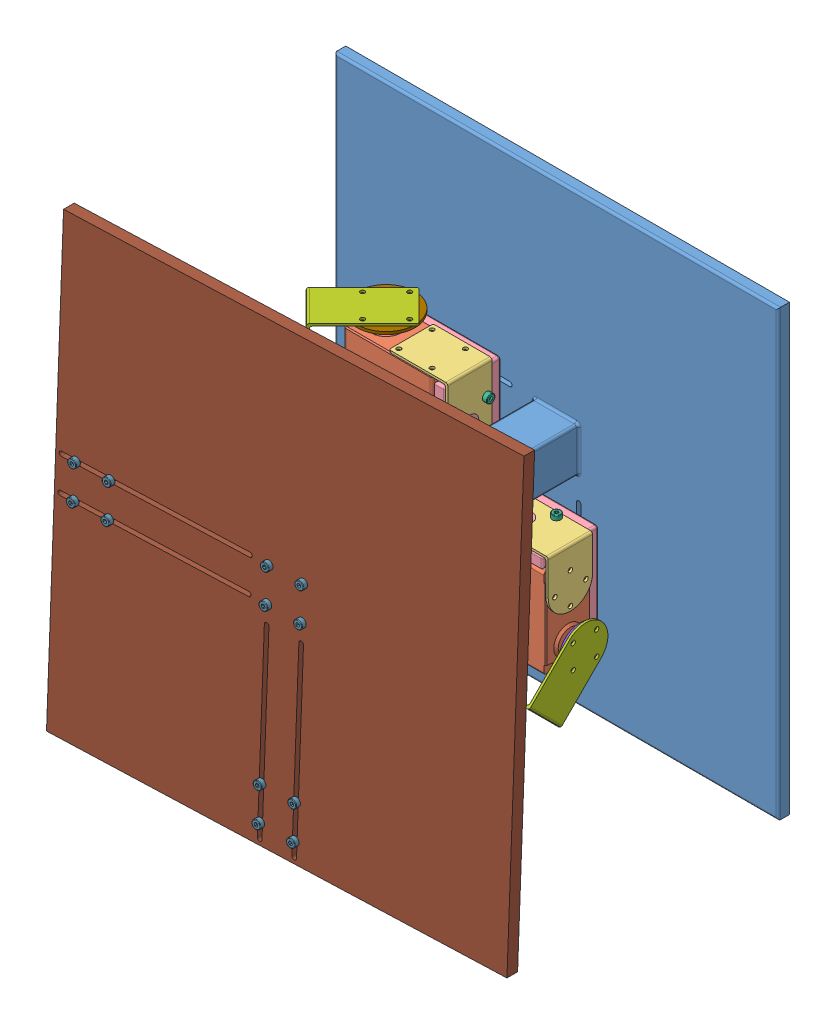
SolidWorks assembly systeme, configuration Défaut. Lengths in mm.
Overall size (200.85 201.15 137.65).
92 component instances, 17 part files, 49 mates.
Components (placement in the parent):
- socle-1: socle [Défaut] at (-2.0735 3.594 197.5) size (200 200 95)
- moteur-complet-1: moteur-complet [Défaut] at (-58.3742 32.144 216.6116) x (-1 0 0) z (0 -1 0) size (49 25.5 42.5)
  - moteur-1: moteur [Défaut] at (-9.5825 -1.0731 48.8) size (45.5 20 48.8)
  - moteur-support-fixe-1: moteur-support-fixe [Défaut] at (-5.7196 9.1116 16.94) x (1 0 0) z (0 -1 0) size (26.58 42.5 20)
  - moteur_semelle-1: moteur_semelle [Défaut] at (-31.3007 -10.8884 28.55) x (-1 0 0) z (0 0 1) size (47 25 38)
  - ecrou-h-m2-1: ecrou-h-m2 [6007 HU M2] at (-27.7007 -8.3884 21.05) x (0 0.5 -0.866025) z (0 -0.866025 -0.5) size (4 1.6 4.62)
  - ecrou-h-m2-2: ecrou-h-m2 [6007 HU M2] at (-27.7007 -8.3884 36.05) x (0 -0.5 -0.866025) z (0 -0.866025 0.5) size (4 1.6 4.62)
  - ecrou-h-m2-3: ecrou-h-m2 [6007 HU M2] at (-27.7007 6.6116 36.05) x (0 -0.5 -0.866025) z (0 -0.866025 0.5) size (4 1.6 4.62)
  - ecrou-h-m2-4: ecrou-h-m2 [6007 HU M2] at (-27.7007 6.6116 21.05) x (0 -1 0) z (0 0 1) size (4 1.6 4.62)
  - vis-chc-m2x5-1: vis-chc-m2x5 [Vis CHC M2x5] at (-32.3007 -8.3884 36.05) x (0 -0.454411 0.890792) z (0 -0.890792 -0.454411) size (3.8 7 3.8)
  - vis-chc-m2x5-2: vis-chc-m2x5 [Vis CHC M2x5] at (-32.3007 6.6116 36.05) x (0 -0.381849 0.924225) z (0 -0.924225 -0.381849) size (3.8 7 3.8)
  - vis-chc-m2x5-3: vis-chc-m2x5 [Vis CHC M2x5] at (-32.3007 6.6116 21.05) x (0 -0.381849 0.924225) z (0 -0.924225 -0.381849) size (3.8 7 3.8)
  - vis-chc-m2x5-4: vis-chc-m2x5 [Vis CHC M2x5] at (-32.3007 -8.3884 21.05) x (0 -0.381849 0.924225) z (0 -0.924225 -0.381849) size (3.8 7 3.8)
- moteur-complet-2: moteur-complet [Défaut] at (-30.6235 -52.7067 216.6116) x (0 -1 0) z (1 0 0) size (49 25.5 42.5)
  - moteur-1: moteur [Défaut] at (-9.5825 -1.0731 48.8) size (45.5 20 48.8)
  - moteur-support-fixe-1: moteur-support-fixe [Défaut] at (-5.7196 9.1116 16.94) x (1 0 0) z (0 -1 0) size (26.58 42.5 20)
  - moteur_semelle-1: moteur_semelle [Défaut] at (-31.3007 -10.8884 28.55) x (-1 0 0) z (0 0 1) size (47 25 38)
  - ecrou-h-m2-1: ecrou-h-m2 [6007 HU M2] at (-27.7007 -8.3884 21.05) x (0 0.5 -0.866025) z (0 -0.866025 -0.5) size (4 1.6 4.62)
  - ecrou-h-m2-2: ecrou-h-m2 [6007 HU M2] at (-27.7007 -8.3884 36.05) x (0 -0.5 -0.866025) z (0 -0.866025 0.5) size (4 1.6 4.62)
  - ecrou-h-m2-3: ecrou-h-m2 [6007 HU M2] at (-27.7007 6.6116 36.05) x (0 -0.5 -0.866025) z (0 -0.866025 0.5) size (4 1.6 4.62)
  - ecrou-h-m2-4: ecrou-h-m2 [6007 HU M2] at (-27.7007 6.6116 21.05) x (0 -1 0) z (0 0 1) size (4 1.6 4.62)
  - vis-chc-m2x5-1: vis-chc-m2x5 [Vis CHC M2x5] at (-32.3007 -8.3884 36.05) x (0 -0.454411 0.890792) z (0 -0.890792 -0.454411) size (3.8 7 3.8)
  - vis-chc-m2x5-2: vis-chc-m2x5 [Vis CHC M2x5] at (-32.3007 6.6116 36.05) x (0 -0.381849 0.924225) z (0 -0.924225 -0.381849) size (3.8 7 3.8)
  - vis-chc-m2x5-3: vis-chc-m2x5 [Vis CHC M2x5] at (-32.3007 6.6116 21.05) x (0 -0.381849 0.924225) z (0 -0.924225 -0.381849) size (3.8 7 3.8)
  - vis-chc-m2x5-4: vis-chc-m2x5 [Vis CHC M2x5] at (-32.3007 -8.3884 21.05) x (0 -0.381849 0.924225) z (0 -0.924225 -0.381849) size (3.8 7 3.8)
- moteur-bras-1: moteur-bras [Défaut] at (-107.7374 1.0095 182.7308) x (0 -1 0) z (0.707107 0 0.707107) size (55.6 52.94 26.87)
  - moteur-support-mobile-1: moteur-support-mobile [Predeterminado] at (-2.6711 -19.0691 55.102) size (55.6 36 20)
  - accessory 1-1: accessory 1 [Predeterminado] at (23.0165 -1.737 35.5744) x (0 -0.707107 -0.707107) z (0 -0.707107 0.707107) size (19 5.06 19)
  - accessory 2-1: accessory 2 [Predeterminado] at (-28.1835 -4.1518 33.4681) x (0 0 -1) z (0 1 0) size (26 5.1 26)
  - support-petite_fourchette-chc_m2-1: support-petite_fourchette-chc_m2 [Défaut] at (-2.5835 -28.0691 55.602) x (-1 0 0) z (0 0 1) size (20 15 20)
  - vis-chc-m2x5-1: vis-chc-m2x5 [Vis CHC M2x5] at (4.9165 -21.0691 63.102) x (-0.837169 0 -0.546944) z (-0.546944 0 0.837169) size (3.8 7 3.8)
  - ecrou-h-m2-1: ecrou-h-m2 [6007 HU M2] at (4.9165 -16.4691 63.102) x (0.866025 0 -0.5) z (0.5 0 0.866025) size (4 1.6 4.62)
  - vis-chc-m2x5-2: vis-chc-m2x5 [Vis CHC M2x5] at (4.9165 -21.0691 48.102) x (-0.837169 0 -0.546944) z (-0.546944 0 0.837169) size (3.8 7 3.8)
  - vis-chc-m2x5-3: vis-chc-m2x5 [Vis CHC M2x5] at (-10.0835 -21.0691 63.102) x (-0.837169 0 -0.546944) z (-0.546944 0 0.837169) size (3.8 7 3.8)
  - vis-chc-m2x5-4: vis-chc-m2x5 [Vis CHC M2x5] at (-10.0835 -21.0691 48.102) x (-0.837169 0 -0.546944) z (-0.546944 0 0.837169) size (3.8 7 3.8)
  - ecrou-h-m2-2: ecrou-h-m2 [6007 HU M2] at (-10.0835 -16.4691 63.102) x (0.866025 0 -0.5) z (0.5 0 0.866025) size (4 1.6 4.62)
  - ecrou-h-m2-3: ecrou-h-m2 [6007 HU M2] at (-10.0835 -16.4691 48.102) x (0.866025 0 -0.5) z (0.5 0 0.866025) size (4 1.6 4.62)
  - ecrou-h-m2-4: ecrou-h-m2 [6007 HU M2] at (4.9165 -16.4691 48.102) x (0.866025 0 0.5) z (-0.5 0 0.866025) size (4 1.6 4.62)
- moteur-bras-2: moteur-bras [Défaut] at (0.5111 -102.0699 182.7308) x (1 0 0) z (0 0.707107 0.707107) size (55.6 52.94 26.87)
  - moteur-support-mobile-1: moteur-support-mobile [Predeterminado] at (-2.6711 -19.0691 55.102) size (55.6 36 20)
  - accessory 1-1: accessory 1 [Predeterminado] at (23.0165 -1.737 35.5744) x (0 -0.707107 -0.707107) z (0 -0.707107 0.707107) size (19 5.06 19)
  - accessory 2-1: accessory 2 [Predeterminado] at (-28.1835 -4.1518 33.4681) x (0 0 -1) z (0 1 0) size (26 5.1 26)
  - support-petite_fourchette-chc_m2-1: support-petite_fourchette-chc_m2 [Défaut] at (-2.5835 -28.0691 55.602) x (-1 0 0) z (0 0 1) size (20 15 20)
  - vis-chc-m2x5-1: vis-chc-m2x5 [Vis CHC M2x5] at (4.9165 -21.0691 63.102) x (-0.837169 0 -0.546944) z (-0.546944 0 0.837169) size (3.8 7 3.8)
  - ecrou-h-m2-1: ecrou-h-m2 [6007 HU M2] at (4.9165 -16.4691 63.102) x (0.866025 0 -0.5) z (0.5 0 0.866025) size (4 1.6 4.62)
  - vis-chc-m2x5-2: vis-chc-m2x5 [Vis CHC M2x5] at (4.9165 -21.0691 48.102) x (-0.837169 0 -0.546944) z (-0.546944 0 0.837169) size (3.8 7 3.8)
  - vis-chc-m2x5-3: vis-chc-m2x5 [Vis CHC M2x5] at (-10.0835 -21.0691 63.102) x (-0.837169 0 -0.546944) z (-0.546944 0 0.837169) size (3.8 7 3.8)
  - vis-chc-m2x5-4: vis-chc-m2x5 [Vis CHC M2x5] at (-10.0835 -21.0691 48.102) x (-0.837169 0 -0.546944) z (-0.546944 0 0.837169) size (3.8 7 3.8)
  - ecrou-h-m2-2: ecrou-h-m2 [6007 HU M2] at (-10.0835 -16.4691 63.102) x (0.866025 0 -0.5) z (0.5 0 0.866025) size (4 1.6 4.62)
  - ecrou-h-m2-3: ecrou-h-m2 [6007 HU M2] at (-10.0835 -16.4691 48.102) x (0.866025 0 -0.5) z (0.5 0 0.866025) size (4 1.6 4.62)
  - ecrou-h-m2-4: ecrou-h-m2 [6007 HU M2] at (4.9165 -16.4691 48.102) x (0.866025 0 0.5) z (-0.5 0 0.866025) size (4 1.6 4.62)
- plateau-complet-3: plateau-complet [Défaut] at (-0.8555 -26.4046 123.8345) x (0 0.999262 -0.038419) z (0.038393 0.038391 0.998525) size (200 200 26)
  - plateau-1: plateau [Défaut] at (22.8083 8.2939 197.5) size (200 200 8)
  - support-sphere-ecrou_m2-4: support-sphere-ecrou_m2 [Défaut] at (-60.8917 8.2939 184.1699) x (1 0 0) z (0 1 0) size (20 18.33 20)
  - support-sphere-ecrou_m2-3: support-sphere-ecrou_m2 [Défaut] at (22.8083 91.9939 184.1699) x (1 0 0) z (0 1 0) size (20 18.33 20)
  - support-fourchette-ecrou_m2-1: support-fourchette-ecrou_m2 [Défaut] at (22.8083 8.2939 183.5) x (1 0 0) z (0 1 0) size (20 19 20)
  - ecrou-h-m2-6: ecrou-h-m2 [6007 HU M2] at (30.3083 99.4939 195.1) x (0.866025 -0.5 0) z (-0.5 -0.866025 0) size (4 1.6 4.62)
  - ecrou-h-m2-7: ecrou-h-m2 [6007 HU M2] at (15.3083 84.4939 195.1) x (-0.866025 -0.5 0) z (-0.5 0.866025 0) size (4 1.6 4.62)
  - ecrou-h-m2-8: ecrou-h-m2 [6007 HU M2] at (30.3083 84.4939 195.1) x (0.866025 0.5 0) z (0.5 -0.866025 0) size (4 1.6 4.62)
  - ecrou-h-m2-9: ecrou-h-m2 [6007 HU M2] at (15.3083 99.4939 195.1) x (0 -1 0) z (-1 0 0) size (4 1.6 4.62)
  - ecrou-h-m2-10: ecrou-h-m2 [6007 HU M2] at (-68.3917 0.7939 195.1) x (0.866025 -0.5 0) z (-0.5 -0.866025 0) size (4 1.6 4.62)
  - ecrou-h-m2-11: ecrou-h-m2 [6007 HU M2] at (-53.3917 0.7939 195.1) x (-0.866025 0.5 0) z (0.5 0.866025 0) size (4 1.6 4.62)
  - ecrou-h-m2-12: ecrou-h-m2 [6007 HU M2] at (-53.3917 15.7939 195.1) x (0.866025 0.5 0) z (0.5 -0.866025 0) size (4 1.6 4.62)
  - ecrou-h-m2-13: ecrou-h-m2 [6007 HU M2] at (-68.3917 15.7939 195.1) x (0.866025 -0.5 0) z (-0.5 -0.866025 0) size (4 1.6 4.62)
  - vis-chc-m2x10-15: vis-chc-m2x10 [Vis CHC M2x10] at (-53.3917 15.7939 202.5) x (0.832658 0.553787 0) z (0.553787 -0.832658 0) size (3.8 12 3.8)
  - vis-chc-m2x10-12: vis-chc-m2x10 [Vis CHC M2x10] at (-68.3917 15.7939 202.5) x (0.872712 0.488236 0) z (0.488236 -0.872712 0) size (3.8 12 3.8)
  - vis-chc-m2x10-14: vis-chc-m2x10 [Vis CHC M2x10] at (-53.3917 0.7939 202.5) x (0.878735 -0.477309 0) z (-0.477309 -0.878735 0) size (3.8 12 3.8)
  - vis-chc-m2x10-13: vis-chc-m2x10 [Vis CHC M2x10] at (-68.3917 0.7939 202.5) x (-0.020688 -0.999786 0) z (-0.999786 0.020688 0) size (3.8 12 3.8)
  - vis-chc-m2x10-10: vis-chc-m2x10 [Vis CHC M2x10] at (15.3083 84.4939 202.5) x (-0.459945 -0.887947 0) z (-0.887947 0.459945 0) size (3.8 12 3.8)
  - vis-chc-m2x10-11: vis-chc-m2x10 [Vis CHC M2x10] at (30.3083 84.4939 202.5) x (-0.307246 0.95163 0) z (0.95163 0.307246 0) size (3.8 12 3.8)
  - vis-chc-m2x10-9: vis-chc-m2x10 [Vis CHC M2x10] at (15.3083 99.4939 202.5) x (0.103271 -0.994653 0) z (-0.994653 -0.103271 0) size (3.8 12 3.8)
  - vis-chc-m2x10-8: vis-chc-m2x10 [Vis CHC M2x10] at (30.3083 99.4939 202.5) x (0.948564 0.316586 0) z (0.316586 -0.948564 0) size (3.8 12 3.8)
  - ecrou-h-m2-14: ecrou-h-m2 [6007 HU M2] at (15.3083 15.7939 195.16) x (0.866025 -0.5 0) z (-0.5 -0.866025 0) size (4 1.6 4.62)
  - ecrou-h-m2-15: ecrou-h-m2 [6007 HU M2] at (15.3083 0.7939 195.16) x (0 -1 0) z (-1 0 0) size (4 1.6 4.62)
  - ecrou-h-m2-16: ecrou-h-m2 [6007 HU M2] at (30.3083 0.7939 195.16) x (0.866025 -0.5 0) z (-0.5 -0.866025 0) size (4 1.6 4.62)
  - ecrou-h-m2-17: ecrou-h-m2 [6007 HU M2] at (30.3083 15.7939 195.16) x (0.866025 -0.5 0) z (-0.5 -0.866025 0) size (4 1.6 4.62)
  - vis-chc-m2x10-16: vis-chc-m2x10 [Vis CHC M2x10] at (15.3083 15.7939 202.5) x (0.719096 0.694911 0) z (0.694911 -0.719096 0) size (3.8 12 3.8)
  - vis-chc-m2x10-17: vis-chc-m2x10 [Vis CHC M2x10] at (30.3083 15.7939 202.5) x (0.587191 0.809448 0) z (0.809448 -0.587191 0) size (3.8 12 3.8)
  - vis-chc-m2x10-18: vis-chc-m2x10 [Vis CHC M2x10] at (15.3083 0.7939 202.5) x (0.239044 0.971009 0) z (0.971009 -0.239044 0) size (3.8 12 3.8)
  - vis-chc-m2x10-19: vis-chc-m2x10 [Vis CHC M2x10] at (30.3083 0.7939 202.5) x (0.971464 0.237189 0) z (0.237189 -0.971464 0) size (3.8 12 3.8)
- support-fourchette-chc_m2-1: support-fourchette-chc_m2 [Défaut] at (-2.0735 3.594 306.5) x (1 0 0) z (0 -1 0) size (20 19 20)
- support-fourchette_axes-1: support-fourchette_axes [Défaut] at (-2.0982 3.594 306.5) x (1 0 0) z (0 0.999262 -0.038419) size (30 5 30)
- bras-cavite-pivot-1: bras-cavite-pivot [Défaut] at (-2.0725 -80.1686 310.3904) x (0 0.99937 -0.035491) z (1 0 0) size (13.96 72.54 20)
- bras-cavite-pivot-2: bras-cavite-pivot [Défaut] at (-85.7108 3.593 310.3858) x (0.999303 0 -0.037321) z (0 -1 0) size (13.96 72.54 20)
- vis-chc-m2x10-1: vis-chc-m2x10 [Vis CHC M2x10] at (-9.5735 -3.906 294.5) x (-0.923728 -0.383049 0) z (-0.383049 0.923728 0) size (3.8 12 3.8)
- vis-chc-m2x10-2: vis-chc-m2x10 [Vis CHC M2x10] at (5.4265 -3.906 294.5) x (-0.923728 -0.383049 0) z (-0.383049 0.923728 0) size (3.8 12 3.8)
- vis-chc-m2x10-3: vis-chc-m2x10 [Vis CHC M2x10] at (-9.5735 11.094 294.5) x (-0.923728 -0.383049 0) z (-0.383049 0.923728 0) size (3.8 12 3.8)
- vis-chc-m2x10-4: vis-chc-m2x10 [Vis CHC M2x10] at (5.4265 11.094 294.5) x (-0.923728 -0.383049 0) z (-0.383049 0.923728 0) size (3.8 12 3.8)
- ecrou-h-m2-1: ecrou-h-m2 [6007 HU M2] at (5.4265 -3.906 285.9) x (0.999229 -0.039254 0) z (0.039254 0.999229 0) size (4 1.6 4.62)
- ecrou-h-m2-2: ecrou-h-m2 [6007 HU M2] at (-9.5735 11.094 285.9) x (-0.5 -0.866025 0) z (0.866025 -0.5 0) size (4 1.6 4.62)
- ecrou-h-m2-3: ecrou-h-m2 [6007 HU M2] at (5.4265 11.094 285.9) x (0.5 -0.866025 0) z (0.866025 0.5 0) size (4 1.6 4.62)
- ecrou-h-m2-4: ecrou-h-m2 [6007 HU M2] at (-9.5735 -3.906 287.5) x (1 0 0) z (0 -1 0) size (4 1.6 4.62)
Mates (geometry in assembly coordinates):
- Coïncidente1: coincident anti-aligned: plane of socle-1 through (-2.0735 3.594 207.5) normal (0 0 1); plane of moteur-complet-1/moteur-1 through (-33.0735 23.844 207.5) normal (0 0 -1)
- Parallèle1: parallel aligned: plane of socle-1 through (97.9265 103.594 202.5) normal (1 0 0); plane of moteur-complet-1/moteur-support-fixe-1 through (-26.0735 -16.656 227.5) normal (1 0 0)
- Coïncidente3: coincident anti-aligned: plane of socle-1 through (-2.0735 3.594 207.5) normal (0 0 1); plane of moteur-complet-2/moteur-1 through (-22.3235 -27.406 207.5) normal (0 0 -1)
- Parallèle2: parallel anti-aligned: plane of socle-1 through (-102.0735 -96.406 202.5) normal (0 -1 0); plane of moteur-complet-2/moteur-support-fixe-1 through (18.1765 -20.406 227.5) normal (0 1 0)
- Distance1: distance = 78.75 mm aligned: plane of moteur-complet-2/support_fixe-1 through (19.1765 -46.406 227.5) normal (1 0 0); plane of socle-1 through (97.9265 103.594 202.5) normal (1 0 0)
- Distance2: distance = 78.75 mm aligned: plane of moteur-complet-1/support_fixe-1 through (-52.0735 -17.656 227.5) normal (0 -1 0); plane of socle-1 through (-102.0735 -96.406 202.5) normal (0 -1 0)
- Coaxiale4: concentric aligned: cylinder of moteur-complet-1/moteur-1 through (-63.8735 27.744 217.5) axis (0 -1 0) radius 2.85; cylinder of moteur-bras-1/accessory 1-1 through (-63.8735 -18.107 217.5) axis (0 -1 0) radius 2.85
- Distance7: distance = 7.55 mm aligned: plane of moteur-bras-1/mobile handle-1 through (-82.2583 31.394 235.1777) normal (0 1 0); plane of moteur-complet-1/moteur-1 through (-48.7917 23.844 217.6847) normal (0 1 0)
- Coaxiale5: concentric aligned: cylinder of moteur-complet-2/moteur-1 through (-26.2235 -58.206 217.5) axis (1 0 0) radius 2.85; cylinder of moteur-bras-2/accessory 1-1 through (19.6275 -58.206 217.5) axis (1 0 0) radius 2.85
- Distance8: distance = 7.55 mm aligned: plane of moteur-bras-2/mobile handle-1 through (-29.8735 -76.5907 235.1777) normal (-1 0 0); plane of moteur-complet-2/moteur-1 through (-22.3235 -43.1242 217.6847) normal (-1 0 0)
- Coïncidente22: coincident anti-aligned: plane of socle-1 through (-27.0735 18.594 227.5) normal (1 0 0); plane of moteur-complet-1/moteur-support-fixe-1 through (-27.0735 22.844 227.5) normal (-1 0 0)
- Coïncidente23: coincident anti-aligned: plane of socle-1 through (-17.0735 -21.406 227.5) normal (0 1 0); plane of moteur-complet-2/moteur-support-fixe-1 through (-21.3235 -21.406 227.5) normal (0 -1 0)
- Coïncidente24: coincident anti-aligned: plane of socle-1 through (-2.0735 3.594 292.5) normal (0 0 1); plane of support-fourchette-1 through (-2.0735 3.594 292.5) normal (0 0 -1)
- Coïncidente25: coincident aligned: plane of socle-1 through (7.9265 13.594 292.5) normal (1 0 0); plane of support-fourchette-1 through (7.9265 3.594 306.5) normal (1 0 0)
- Coïncidente26: coincident aligned: plane of socle-1 through (-12.0735 -6.406 292.5) normal (0 -1 0); plane of support-fourchette-1 through (-12.0735 -6.406 292.5) normal (0 -1 0)
- Coaxiale16: concentric anti-aligned: cylinder of support-fourchette-1 through (7.9265 3.594 306.5) axis (-1 0 0) radius 2.5; circle of support-fourchette_axes-1
- Coaxiale18: concentric anti-aligned: cylinder of moteur-bras-2/support-fourchette_petites-1 through (-12.0725 -82.6011 241.8952) axis (1 0 0) radius 2.5; cylinder of bras-cavite-pivot-1 through (7.9275 -82.6011 241.8952) axis (-1 0 0) radius 2.5
- Coïncidente31: coincident aligned: plane of moteur-bras-2/support-fourchette_petites-1 through (7.9275 -82.6011 241.8952) normal (1 0 0); plane of bras-cavite-pivot-1 through (7.9275 -82.6011 241.8952) normal (1 0 0)
- Coaxiale20: concentric anti-aligned: cylinder of moteur-bras-1/support-petite_fourchette-1 through (-88.2687 13.593 241.8952) axis (0 -1 0) radius 2.5; cylinder of bras-cavite-pivot-2 through (-88.2687 -6.407 241.8952) axis (0 1 0) radius 2.5
- Coïncidente32: coincident aligned: plane of moteur-bras-1/support-petite_fourchette-1 through (-88.2687 -6.407 241.8952) normal (0 -1 0); plane of bras-cavite-pivot-2 through (-88.2687 -6.407 241.8952) normal (0 -1 0)
- Coïncidente33: coincident aligned: plane of plateau-complet-3/support-fourchette-1; plane of support-fourchette-1 through (-12.0735 -6.406 292.5) normal (0 -1 0)
- Coïncidente34: coincident aligned: plane of plateau-complet-3/support-fourchette-1; plane of support-fourchette-1 through (7.9265 3.594 306.5) normal (1 0 0)
- Coaxiale21: concentric aligned: cylinder of plateau-complet-3/support-fourchette-1 through (-2.0982 13.4365 306.1216) axis (0 -0.999262 0.038419) radius 2.5; cylinder of support-fourchette_axes-1 through (-2.0982 18.583 305.9237) axis (0 -0.999262 0.038419) radius 2.5
- Coaxiale23: concentric: sphere of plateau-complet-3/support-sphere-2; sphere of bras-cavite-pivot-1
- Coaxiale24: concentric: sphere of plateau-complet-3/support-sphere-ecrou_m2-4; sphere of bras-cavite-pivot-1
- Coaxiale25: concentric: sphere of plateau-complet-3/support-sphere-ecrou_m2-3; sphere of bras-cavite-pivot-2
- Angle1: planar angle = 2.356194 rad anti-aligned: plane of moteur-bras-2/mobile handle-1 through (-29.8725 -68.459 241.8952) normal (0 0.707107 0.707107); plane of moteur-complet-2/moteur-1 through (-22.3235 -27.406 227.5) normal (0 0 1)
- Angle2: planar angle = 2.356194 rad anti-aligned: plane of moteur-bras-1/mobile handle-1 through (-74.1265 31.393 241.8952) normal (0.707107 0 0.707107); plane of moteur-complet-1/moteur-1 through (-33.0735 23.844 227.5) normal (0 0 1)
- Angle3: planar angle = 2.879793 rad anti-aligned: plane of moteur-bras-1/mobile handle-1 through (-68.546 31.393 243.5465) normal (0.844575 0 0.535438); plane of moteur-complet-1/moteur-1 through (-33.0735 23.844 227.5) normal (0 0 1)
- Angle4: planar angle = 2.879793 rad anti-aligned: plane of moteur-complet-2/moteur-1 through (-22.3235 -27.406 227.5) normal (0 0 1); plane of moteur-bras-2/mobile handle-1 through (-29.8725 -68.459 241.8952) normal (0 0.707107 0.707107)
- Coaxiale26: concentric aligned: cylinder of support-fourchette-1 through (-9.5735 -3.906 292.499) axis (0 0 1) radius 1; cylinder of vis-chc-m2x10-1 through (-9.5735 -3.906 284.5) axis (0 0 1) radius 1
- Coïncidente35: coincident anti-aligned: plane of support-fourchette-1 through (-9.5735 -3.906 294.5) normal (0 0 1); plane of vis-chc-m2x10-1 through (-9.5735 -3.906 294.5) normal (0 0 -1)
- Coaxiale27: concentric aligned: cylinder of support-fourchette-1 through (5.4265 -3.906 292.499) axis (0 0 1) radius 1; cylinder of vis-chc-m2x10-2 through (5.4265 -3.906 284.5) axis (0 0 1) radius 1
- Coïncidente36: coincident anti-aligned: plane of support-fourchette-1 through (5.4265 -3.906 294.5) normal (0 0 1); plane of vis-chc-m2x10-2 through (5.4265 -3.906 294.5) normal (0 0 -1)
- Coaxiale28: concentric aligned: cylinder of support-fourchette-1 through (-9.5735 11.094 292.499) axis (0 0 1) radius 1; cylinder of vis-chc-m2x10-3 through (-9.5735 11.094 284.5) axis (0 0 1) radius 1
- Coïncidente37: coincident anti-aligned: plane of support-fourchette-1 through (-9.5735 11.094 294.5) normal (0 0 1); plane of vis-chc-m2x10-3 through (-9.5735 11.094 294.5) normal (0 0 -1)
- Coaxiale29: concentric aligned: cylinder of support-fourchette-1 through (5.4265 11.094 292.499) axis (0 0 1) radius 1; cylinder of vis-chc-m2x10-4 through (5.4265 11.094 284.5) axis (0 0 1) radius 1
- Coïncidente38: coincident anti-aligned: plane of support-fourchette-1 through (5.4265 11.094 294.5) normal (0 0 1); plane of vis-chc-m2x10-4 through (5.4265 11.094 294.5) normal (0 0 -1)
- Coaxiale30: concentric anti-aligned: cylinder of vis-chc-m2x10-2 through (5.4265 -3.906 284.5) axis (0 0 1) radius 1; cylinder of ecrou-h-m2-1 through (5.4265 -3.906 287.5) axis (0 0 -1) radius 0.7835
- Coïncidente39: coincident anti-aligned: plane of socle-1 through (7.9265 -1.406 287.5) normal (0 0 -1); plane of ecrou-h-m2-1 through (7.3796 -5.1383 287.5) normal (0 0 1)
- Coïncidente41: coincident anti-aligned: plane of ecrou-h-m2-4 through (-7.5735 -2.7513 287.5) normal (0 0 1); plane of socle-1 through (-12.0735 -1.406 287.5) normal (0 0 -1)
- Coaxiale35: concentric aligned: cylinder of vis-chc-m2x10-1 through (-9.5735 -3.906 284.5) axis (0 0 1) radius 1; cylinder of ecrou-h-m2-4 through (-9.5735 -3.906 285.9) axis (0 0 1) radius 0.7835
- Coïncidente44: coincident anti-aligned: plane of socle-1 through (-7.5735 -1.406 287.5) normal (-1 0 0); plane of ecrou-h-m2-4 through (-7.5735 -5.0607 285.9) normal (1 0 0)
- Coïncidente45: coincident anti-aligned: plane of socle-1 through (-12.0735 8.594 287.5) normal (0 0 -1); plane of ecrou-h-m2-2 through (-11.5735 9.9393 287.5) normal (0 0 1)
- Coaxiale36: concentric anti-aligned: cylinder of vis-chc-m2x10-3 through (-9.5735 11.094 284.5) axis (0 0 1) radius 1; cylinder of ecrou-h-m2-2 through (-9.5735 11.094 287.5) axis (0 0 -1) radius 0.7835
- Coïncidente48: coincident anti-aligned: plane of socle-1 through (-7.5735 8.594 287.5) normal (-1 0 0); plane of ecrou-h-m2-2 through (-7.5735 12.2487 287.5) normal (1 0 0)
- Coaxiale37: concentric anti-aligned: cylinder of vis-chc-m2x10-4 through (5.4265 11.094 284.5) axis (0 0 1) radius 1; cylinder of ecrou-h-m2-3 through (5.4265 11.094 287.5) axis (0 0 -1) radius 0.7835
- Coïncidente50: coincident anti-aligned: plane of socle-1 through (3.4265 8.594 287.5) normal (1 0 0); plane of ecrou-h-m2-3 through (3.4265 9.9393 287.5) normal (-1 0 0)
- Coïncidente51: coincident anti-aligned: plane of socle-1 through (7.9265 8.594 287.5) normal (0 0 -1); plane of ecrou-h-m2-3 through (5.4265 8.7846 287.5) normal (0 0 1)
